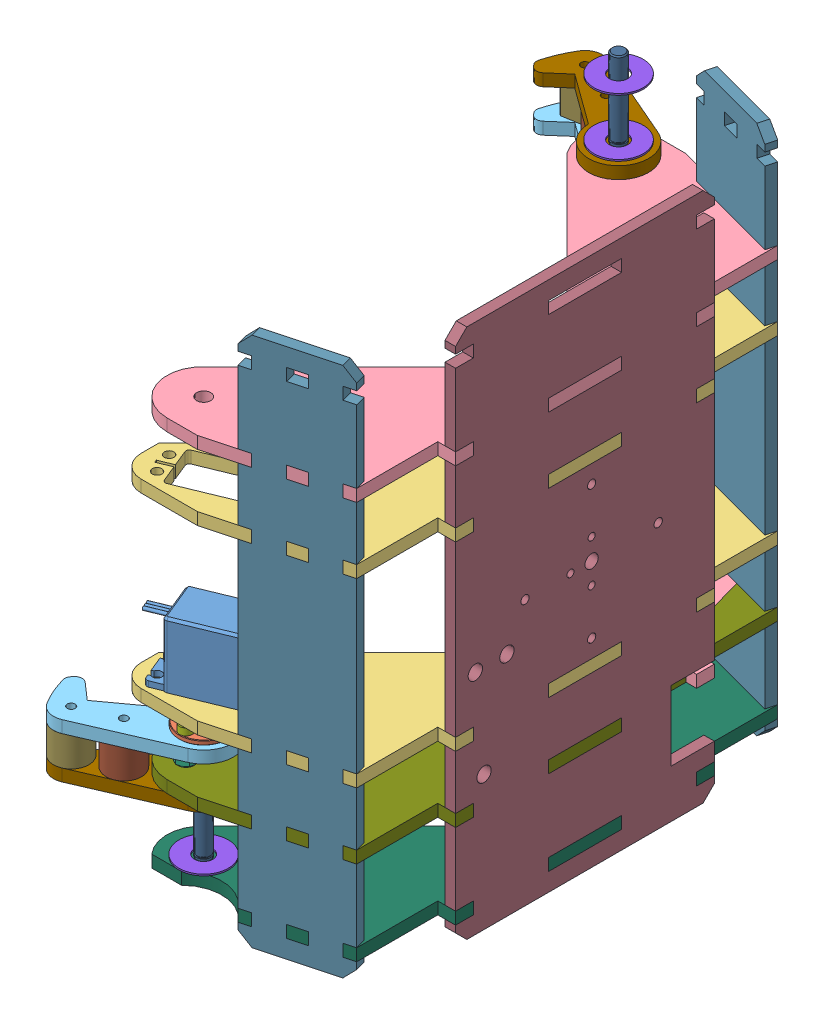
SolidWorks assembly Double Gripper Assm rA.01, configuration Default. Lengths in mm.
Overall size (128.06 238.98 252.3).
47 component instances, 19 part files, 12 mates.
Components (placement in the parent):
- Gripper Assm rA.01-1: Gripper Assm rA.01 [Default] at origin size (128.06 105.71 236.15)
  - 1718 GLYPH BLACK-1: 1718 GLYPH BLACK [Default] at (-76.2 0 0) size (152.4 152.4 152.4) (hidden)
  - 1718 GLYPH BLACK-2: 1718 GLYPH BLACK [Default] at (-152.4 0 0) x (0.707107 0 0.707107) z (-0.707107 0 0.707107) size (152.4 152.4 152.4) (hidden)
  - Grabber Paddle-1: Grabber Paddle [Default] at origin
  - TETRIX_739197_SERVO_2012-1: TETRIX_739197_SERVO_2012 [Default] at (-7.184 35.6 -93.4511) x (-0.380109 0 0.924942) z (-0.924942 0 -0.380109) size (20 43.2 56.76)
  - 8699-17-307 Gripper Mount Structure-1: 8699-17-307 Gripper Mount Structure [Default] at origin
  - Tetrix Servo Hub Metal Light Duty-1: Tetrix Servo Hub Metal Light Duty [Default] at (-7.184 55.1 -93.4511) size (22 6.2 22)
  - 8699-17-314 Gripper Strut ServoMnt-1: 8699-17-314 Gripper Strut ServoMnt [Default] at (63.1261 38.1 0) size (100 5.46 220)
  - 8699-17-315 Gripper Strut Axle-1: 8699-17-315 Gripper Strut Axle [Default] at (63.1261 67.8 0) size (94.86 5.46 220)
  - 8699-17-315 Gripper Strut Axle-2: 8699-17-315 Gripper Strut Axle [Default] at (63.1261 105.9 0) size (94.86 5.46 220) (hidden)
  - 8699-17-316 Gripper Right Servoed-1: 8699-17-316 Gripper Right Servoed [Default] at (-7.184 55.1 -93.4511) size (63.25 5.46 43.7)
  - 90631A007 Hex Nut 6-32 Nyloc LoS-1: 90631A007 Hex Nut 6-32 Nyloc LoS [90631A007] at (-7.184 60.561 -101.4511) size (7.94 4.37 9.17)
  - tetrix_739097 Screw SHC 6-32 0.50Lg-1: tetrix_739097 Screw SHC 6-32 0.50Lg [Default] at (-7.184 53.1 -101.4511) x (-1 0 0) z (0 0 1) size (5.74 16.21 5.74)
  - Washer .31 id-1: Washer .31 id [Default] at (-7.184 73.261 -93.4511) size (22.17 0.71 22.17)
  - 8699-17-317 rC Gripper Right Axled-3: 8699-17-317 rC Gripper Right Axled [Default] at (-7.184 73.9722 -93.4511) size (63.25 5.46 43.7)
  - Washer .31 id-2: Washer .31 id [Default] at (-7.184 105.1888 -93.4511) size (22.17 0.71 22.17)
  - Washer .31 id-3: Washer .31 id [Default] at (-7.184 79.4332 -93.4511) size (22.17 0.71 22.17)
  - 8699-17-318 Shaft - Gripper Grooved-1: 8699-17-318 Shaft - Gripper Grooved [Default] at (-7.184 57.561 -93.4511) size (6.35 57.15 6.35)
  - 8699-17-319 Grippers Dowel Conn-1: 8699-17-319 Grippers Dowel Conn [Default] at (-28.0465 60.561 -108.5448) size (15.88 13.41 15.88)
  - 8699-17-324 Grippers Dowel Conn Front-1: 8699-17-324 Grippers Dowel Conn Front [Default] at (-44.5973 60.561 -115.7104) x (0.917686 0 0.397307) z (-0.397307 0 0.917686) size (15.88 13.41 15.72)
  - 8699-17-317 rC Gripper Right Axled-2: 8699-17-317 rC Gripper Right Axled [Default] at (-7.184 111.361 -93.4511) x (0.997645 0 -0.068586) z (0.068586 0 0.997645) size (63.25 5.46 43.7) (hidden)
- Gripper Assm rA.01-2: Gripper Assm rA.01 [Default] x (1 0 0) z (0 0 -1) size (128.06 105.71 236.15)
  - 1718 GLYPH BLACK-1: 1718 GLYPH BLACK [Default] at (-76.2 0 0) size (152.4 152.4 152.4) (hidden)
  - 1718 GLYPH BLACK-2: 1718 GLYPH BLACK [Default] at (-152.4 0 0) x (0.707107 0 0.707107) z (-0.707107 0 0.707107) size (152.4 152.4 152.4) (hidden)
  - Grabber Paddle-1: Grabber Paddle [Default] at origin
  - TETRIX_739197_SERVO_2012-1: TETRIX_739197_SERVO_2012 [Default] at (-7.184 35.6 -93.4511) x (-0.380109 0 0.924942) z (-0.924942 0 -0.380109) size (20 43.2 56.76)
  - 8699-17-307 Gripper Mount Structure-1: 8699-17-307 Gripper Mount Structure [Default] at origin
  - Tetrix Servo Hub Metal Light Duty-1: Tetrix Servo Hub Metal Light Duty [Default] at (-7.184 55.1 -93.4511) size (22 6.2 22)
  - 8699-17-314 Gripper Strut ServoMnt-1: 8699-17-314 Gripper Strut ServoMnt [Default] at (63.1261 38.1 0) size (100 5.46 220)
  - 8699-17-315 Gripper Strut Axle-1: 8699-17-315 Gripper Strut Axle [Default] at (63.1261 67.8 0) size (94.86 5.46 220)
  - 8699-17-315 Gripper Strut Axle-2: 8699-17-315 Gripper Strut Axle [Default] at (63.1261 105.9 0) size (94.86 5.46 220) (hidden)
  - 8699-17-316 Gripper Right Servoed-1: 8699-17-316 Gripper Right Servoed [Default] at (-7.184 55.1 -93.4511) size (63.25 5.46 43.7)
  - 90631A007 Hex Nut 6-32 Nyloc LoS-1: 90631A007 Hex Nut 6-32 Nyloc LoS [90631A007] at (-7.184 60.561 -101.4511) size (7.94 4.37 9.17)
  - tetrix_739097 Screw SHC 6-32 0.50Lg-1: tetrix_739097 Screw SHC 6-32 0.50Lg [Default] at (-7.184 53.1 -101.4511) x (-1 0 0) z (0 0 1) size (5.74 16.21 5.74)
  - Washer .31 id-1: Washer .31 id [Default] at (-7.184 73.261 -93.4511) size (22.17 0.71 22.17)
  - 8699-17-317 rC Gripper Right Axled-3: 8699-17-317 rC Gripper Right Axled [Default] at (-7.184 73.9722 -93.4511) size (63.25 5.46 43.7)
  - Washer .31 id-2: Washer .31 id [Default] at (-7.184 105.1888 -93.4511) size (22.17 0.71 22.17)
  - Washer .31 id-3: Washer .31 id [Default] at (-7.184 79.4332 -93.4511) size (22.17 0.71 22.17)
  - 8699-17-318 Shaft - Gripper Grooved-1: 8699-17-318 Shaft - Gripper Grooved [Default] at (-7.184 57.561 -93.4511) size (6.35 57.15 6.35)
  - 8699-17-319 Grippers Dowel Conn-1: 8699-17-319 Grippers Dowel Conn [Default] at (-28.0465 60.561 -108.5448) size (15.88 13.41 15.88)
  - 8699-17-324 Grippers Dowel Conn Front-1: 8699-17-324 Grippers Dowel Conn Front [Default] at (-44.5973 60.561 -115.7104) x (0.917686 0 0.397307) z (-0.397307 0 0.917686) size (15.88 13.41 15.72)
  - 8699-17-317 rC Gripper Right Axled-2: 8699-17-317 rC Gripper Right Axled [Default] at (-7.184 111.361 -93.4511) x (0.997645 0 -0.068586) z (0.068586 0 0.997645) size (63.25 5.46 43.7) (hidden)
- 8699-17-320 Grippers Back-1: 8699-17-320 Grippers Back [Default] at (71.1261 0 0) size (4.76 238.98 116.59)
- 8699-17-321 Grippers RightSide-1: 8699-17-321 Grippers RightSide [Default] at (21.0131 0 -106.1177) x (0.965926 0 0.258819) z (-0.258819 0 0.965926) size (43.6 238.98 4.76)
- 8699-17-322 Gripper Strut Axle BtmMost-1: 8699-17-322 Gripper Strut Axle BtmMost [Default] at (63.1261 -105.9 0) x (1 0 0) z (0 0 -1) size (94.86 5.46 212.24)
- 8699-17-321 Grippers RightSide-2: 8699-17-321 Grippers RightSide [Default] at (63.1261 0 94.8336) x (-0.965926 0 0.258819) z (-0.258819 0 -0.965926) size (43.6 238.98 4.76)
- 8699-17-323 Gripper Strut Axle 2ndBtmUp-1: 8699-17-323 Gripper Strut Axle 2ndBtmUp [Default] at (63.1261 -67.8 0) x (1 0 0) z (0 0 -1) size (94.86 5.46 220)
Mates (geometry in assembly coordinates):
- Coincident1: coincident aligned: plane of 8699-17-320 Grippers Back-1 through (71.1261 0 0) normal (0 1 0); plane of assembly through (0 0 0) normal (0 1 0)
- Coincident2: coincident aligned: plane of 8699-17-320 Grippers Back-1 through (71.1261 0 0) normal (0 0 1); plane of assembly through (0 0 0) normal (0 0 1)
- Coincident3: coincident aligned: plane of Gripper Assm rA.01-1/8699-17-315 Gripper Strut Axle-2 through (71.1261 111.361 -58.293) normal (1 0 0); plane of 8699-17-320 Grippers Back-1 through (71.1261 0 0) normal (1 0 0)
- Coincident4: coincident anti-aligned: plane of Gripper Assm rA.01-1/8699-17-314 Gripper Strut ServoMnt-1 through (6.5242 43.561 -110) normal (0.258819 0 -0.965926); plane of 8699-17-321 Grippers RightSide-1 through (21.0131 0 -106.1177) normal (-0.258819 0 0.965926)
- Coincident5: coincident aligned: plane of 8699-17-321 Grippers RightSide-1; plane of assembly through (0 0 0) normal (0 1 0)
- Coincident6: coincident aligned: plane of Gripper Assm rA.01-1/8699-17-315 Gripper Strut Axle-2 through (71.1261 110.6625 -92.69) normal (1 0 0); plane of 8699-17-321 Grippers RightSide-1
- Coincident7: coordinate: point of Gripper Assm rA.01-2/8699-17-315 Gripper Strut Axle-2; point of 8699-17-322 Gripper Strut Axle BtmMost-1
- Coincident8: coincident: plane of 8699-17-321 Grippers RightSide-1 through (21.0131 0 -106.1177) normal (0.965926 0 0.258819); point of 8699-17-322 Gripper Strut Axle BtmMost-1
- Coincident9: coincident anti-aligned: plane of Gripper Assm rA.01-1/8699-17-314 Gripper Strut ServoMnt-1 through (63.1261 43.561 94.8336) normal (0.258819 0 0.965926); plane of 8699-17-321 Grippers RightSide-2 through (63.1261 0 94.8336) normal (-0.258819 0 -0.965926)
- Coincident10: coincident aligned: plane of 8699-17-321 Grippers RightSide-1; plane of 8699-17-321 Grippers RightSide-2
- Coincident11: coincident: point of Gripper Assm rA.01-1/8699-17-314 Gripper Strut ServoMnt-1; plane of 8699-17-321 Grippers RightSide-2 through (61.8935 119.489 90.2333) normal (0.965926 0 -0.258819)
- Coincident12: coordinate: point of Gripper Assm rA.01-2/8699-17-315 Gripper Strut Axle-1; point of 8699-17-323 Gripper Strut Axle 2ndBtmUp-1
